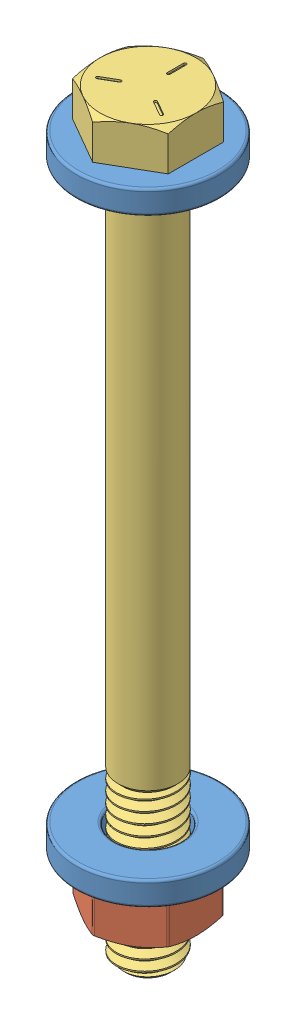
SolidWorks assembly t_slot_longscrew_assembly, configuration Default. Lengths in mm.
Overall size (26.37 100.93 26.37).
4 component instances, 3 part files, 10 mates.
Components (placement in the parent):
- 5-16x.75 oversize washer 91525A326_316 Stainless Steel Washer-3: 5-16x.75 oversize washer 91525A326_316 Stainless Steel Washer [91525A326] at (0 1.5875 0) x (0.837169 0 0.546944) z (0 1 0) size (19.05 19.05 3.17)
- 5-16x.75 oversize washer 91525A326_316 Stainless Steel Washer-4: 5-16x.75 oversize washer 91525A326_316 Stainless Steel Washer [91525A326] at (0 -77.7875 0) x (1 0 0) z (0 -1 0) size (19.05 19.05 3.17)
- 5-18 nut 95462A030_Medium-Strength Steel Hex Nut(1)-1: 5-18 nut 95462A030_Medium-Strength Steel Hex Nut(1) [95462A030] at (0 -82.7484 0) x (0.5 0 -0.866025) z (0 1 0) size (12.7 14.57 7.61)
- 5s16p18x3.75 bolt 91247A598_Medium-Strength Grade 5 Steel Hex Head Screw-1: 5s16p18x3.75 bolt 91247A598_Medium-Strength Grade 5 Steel Hex Head Screw [91247A598] at (0 -41.8703 0) x (0 -1 0) z (-0.5 0 0.866025) size (100.93 14.66 12.7)
Mates (geometry in assembly coordinates):
- Concentric1: concentric aligned: cylinder of 5-16x.75 oversize washer 91525A326_316 Stainless Steel Washer-3 through (0 0 0) axis (0 1 0) radius 4.3688
- Coincident8: coincident anti-aligned: plane of 5-16x.75 oversize washer 91525A326_316 Stainless Steel Washer-3 through (0 0 0) normal (0 -1 0)
- Concentric2: concentric anti-aligned: cylinder of 5-16x.75 oversize washer 91525A326_316 Stainless Steel Washer-3 through (0 0 0) axis (0 1 0) radius 4.3688; cylinder of 5-16x.75 oversize washer 91525A326_316 Stainless Steel Washer-4 through (0 -76.2 0) axis (0 -1 0) radius 4.3688
- Distance1: distance = 76.2 mm anti-aligned: plane of 5-16x.75 oversize washer 91525A326_316 Stainless Steel Washer-4 through (0 -76.2 0) normal (0 1 0); plane of 5-16x.75 oversize washer 91525A326_316 Stainless Steel Washer-3 through (0 0 0) normal (0 -1 0)
- Coincident12: coincident anti-aligned: plane of 5-16x.75 oversize washer 91525A326_316 Stainless Steel Washer-4 through (0 -79.375 0) normal (0 -1 0); plane of 5-18 nut 95462A030_Medium-Strength Steel Hex Nut(1)-1 through (0 -79.375 0) normal (0 1 0)
- Concentric4: concentric anti-aligned: circle of 5-16x.75 oversize washer 91525A326_316 Stainless Steel Washer-4; circle of 5-18 nut 95462A030_Medium-Strength Steel Hex Nut(1)-1
- Coincident14: coincident aligned: plane of 5-16x.75 oversize washer 91525A326_316 Stainless Steel Washer-4 through (0 -77.7875 0) normal (1 0 0)
- Concentric5: concentric anti-aligned: circle of 5-16x.75 oversize washer 91525A326_316 Stainless Steel Washer-3; cylinder of 5s16p18x3.75 bolt 91247A598_Medium-Strength Grade 5 Steel Hex Head Screw-1 through (0 3.175 0) axis (0 -1 0) radius 3.9688
- Coincident15: coincident anti-aligned: plane of 5-16x.75 oversize washer 91525A326_316 Stainless Steel Washer-3 through (0 3.175 0) normal (0 1 0); plane of 5s16p18x3.75 bolt 91247A598_Medium-Strength Grade 5 Steel Hex Head Screw-1 through (0 3.175 7.3323) normal (0 -1 0)
- Parallel1: parallel anti-aligned: plane of 5s16p18x3.75 bolt 91247A598_Medium-Strength Grade 5 Steel Hex Head Screw-1 through (-6.35 8.3344 -3.6662) normal (-1 0 0)
